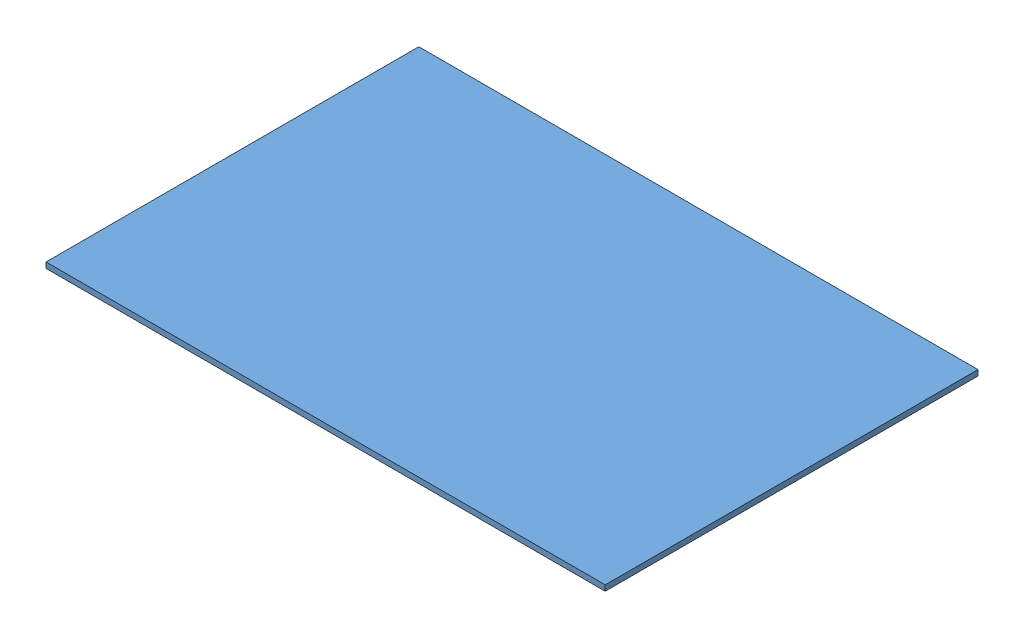
SolidWorks assembly milling-3mm-battery-protector, configuration Default. Lengths in mm.
Overall size (300 3 200).
2 component instances, 2 part files, 3 mates.
Components (placement in the parent):
- carbon-stock-3mm-1: carbon-stock-3mm [Default] at origin size (300 3 200)
- battery-stopper-1: battery-stopper [Default] at (-142.1 0 83.5) x (0 0 1) z (0 1 0) size (31 13.5 3)
Mates (geometry in assembly coordinates):
- Coincident10: coincident aligned: plane of carbon-stock-3mm-1 through (0 0 0) normal (0 -1 0); plane of battery-stopper-1 through (-142.1 0 83.5) normal (0 -1 0)
- Distance12: distance = 1 mm aligned: plane of battery-stopper-1 through (-142.1 3 99) normal (0 0 1); plane of carbon-stock-3mm-1 through (-150 3 100) normal (0 0 1)
- Distance13: distance = 1 mm aligned: plane of battery-stopper-1 through (-149 3 83.5) normal (-1 0 0); plane of carbon-stock-3mm-1 through (-150 3 -100) normal (-1 0 0)
